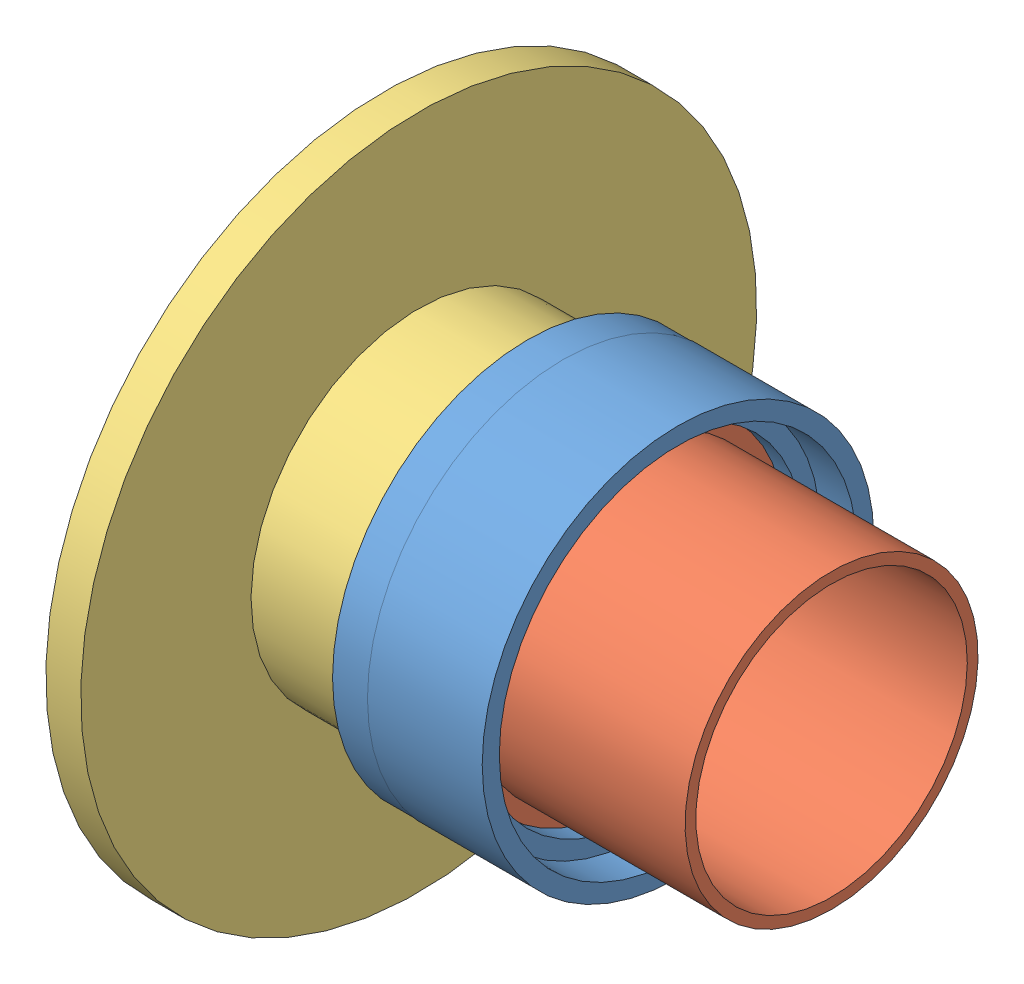
SolidWorks assembly Spring Lock Assembly, configuration Default. Lengths in mm.
Overall size (58.06 95.94 95.94).
3 component instances, 3 part files, 5 mates.
Components (placement in the parent):
- Collar v2-1: Collar v2 [Default] at (-24.9132 34.1407 39.5723) size (15.62 40.74 40.74)
- Plug Core v2-1: Plug Core v2 [Default] at (-27.7326 34.1407 39.5723) x (1 0 0) z (0 0.495788 0.868444) size (34.42 35.66 35.66)
- Receptical v2-1: Receptical v2 [Default] at (-16.963 34.1407 39.5723) x (1 0 0) z (0 0.495788 0.868444) size (34.41 70.33 70.33)
Mates (geometry in assembly coordinates):
- Coincident1: coincident anti-aligned: plane of Collar v2-1 through (-15.0326 34.1407 22.7575) normal (-1 0 0); plane of Plug Core v2-1 through (-15.0326 25.3005 24.0872) normal (1 0 0)
- Concentric1: concentric aligned: circle of Collar v2-1; circle of Plug Core v2-1
- Coincident2: coincident: plane of Plug Core v2-1 through (-27.7326 34.1407 39.5723) normal (0 0.868444 -0.495788); plane of Receptical v2-1 through (-42.6296 34.1407 39.5723) normal (0 0.868444 -0.495788)
- Coincident3: coincident: plane of Plug Core v2-1 through (-27.7326 34.1407 39.5723) normal (0 0.495788 0.868444); plane of Receptical v2-1 through (-42.6296 34.1407 39.5723) normal (0 0.495788 0.868444)
- Coincident4: coincident anti-aligned: plane of Plug Core v2-1 through (-16.963 26.5849 26.3372) normal (-1 0 0); plane of Receptical v2-1 through (-16.963 25.4894 24.4181) normal (1 0 0)
